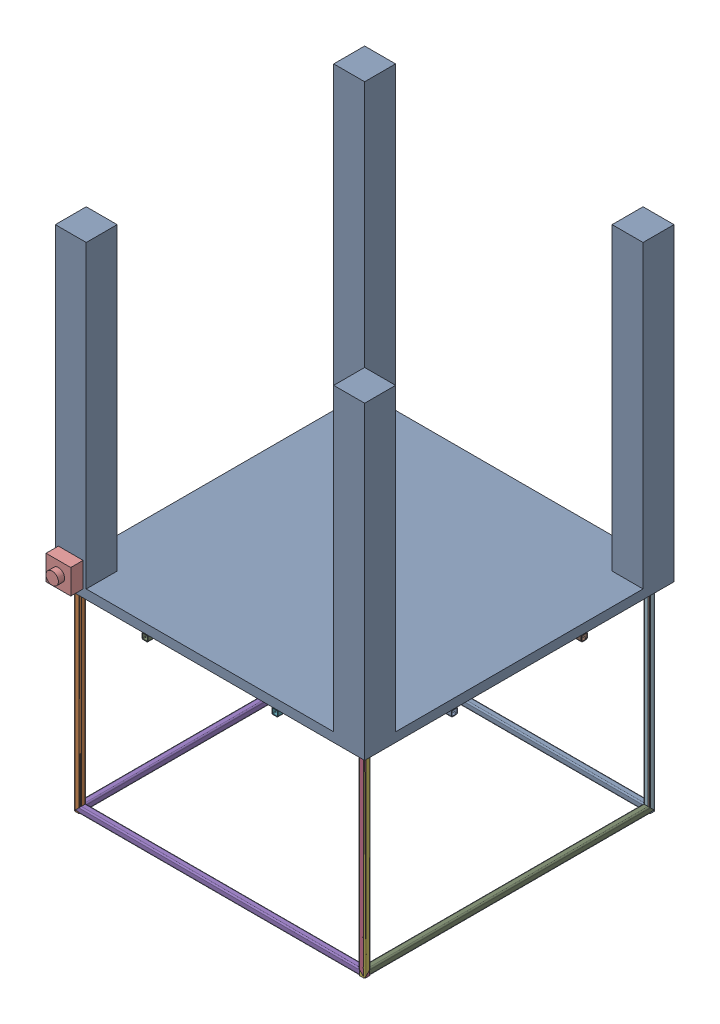
SolidWorks assembly Scenery, configuration Default. Lengths in mm.
Overall size (1000 1640.83 1060).
6 component instances, 3 part files, 12 mates.
Components (placement in the parent):
- Table-1: Table [Default] at (-69.884 -391.2229 -37.0247) size (1000 1000 1000)
- guard-1: guard [Default<As Machined>] at (390.116 -401.2229 422.9753) x (-1 0 0) z (0 0 1) size (940 640.83 80)
- guard-2: guard [Default<As Machined>] at (390.116 -401.2229 -497.0247) x (-1 0 0) z (0 0 1) size (940 640.83 80)
- guard-3: guard [Default<As Machined>] at (390.116 -401.2229 -497.0247) x (0 0 1) z (1 0 0) size (940 640.83 80)
- guard-4: guard [Default<As Machined>] at (-529.884 -401.2229 -497.0247) x (0 0 1) z (1 0 0) size (940 640.83 80)
- eStop-1: eStop [Default] at (-559.884 -366.2229 462.9753) x (1 0 0) z (0 -1 0) size (80 60 80)
Mates (geometry in assembly coordinates):
- Parallel1: parallel anti-aligned: plane of Table-1 through (-69.884 -391.2229 -37.0247) normal (0 -1 0); plane of guard-1 through (-529.884 -391.2229 428.9753) normal (0 1 0)
- Parallel2: parallel aligned: plane of Table-1 through (430.116 -361.2229 -37.0247) normal (1 0 0); plane of guard-1 through (400.116 -1022.0562 428.9753) normal (1 0 0)
- Coincident4: coincident aligned: plane of Table-1 through (-69.884 -361.2229 462.9753) normal (0 0 1); plane of guard-1 through (-285.884 -407.2229 462.9753) normal (0 0 1)
- Parallel3: parallel anti-aligned: plane of Table-1 through (-69.884 -391.2229 -37.0247) normal (0 -1 0); plane of guard-3 through (396.116 -391.2229 422.9753) normal (0 1 0)
- Parallel4: parallel aligned: plane of Table-1 through (-69.884 -361.2229 -537.0247) normal (0 0 -1); plane of guard-3 through (396.116 -1022.0562 -507.0247) normal (0 0 -1)
- Coincident9: coincident aligned: plane of Table-1 through (430.116 -361.2229 -37.0247) normal (1 0 0); plane of guard-3 through (430.116 -407.2229 -241.0247) normal (1 0 0)
- Coincident10: coincident anti-aligned: plane of Table-1 through (-69.884 -391.2229 -37.0247) normal (0 -1 0); plane of guard-3 through (396.116 -391.2229 422.9753) normal (0 1 0)
- Coincident12: coincident: line of guard-3 through (390.116 -1022.0562 -37.0247) axis (0 1 0)
- Coincident13: coincident: line of guard-2 through (-69.884 -1022.0562 -497.0247) axis (0 1 0)
- Parallel6: parallel: plane of Table-1 through (-69.884 -361.2229 462.9753) normal (0 0 1); plane of eStop-1 through (-559.884 -242.9809 462.9753) normal (0 0 -1)
- Distance5: distance = 10 mm: plane of eStop-1 through (-479.884 -366.2229 502.9753) normal (1 0 0); plane of Table-1 through (-469.884 608.7771 -37.0247) normal (1 0 0)
- Distance6: distance = 25 mm aligned: plane of eStop-1 through (-559.884 -366.2229 502.9753) normal (0 -1 0); plane of Table-1 through (-69.884 -391.2229 -37.0247) normal (0 -1 0)
